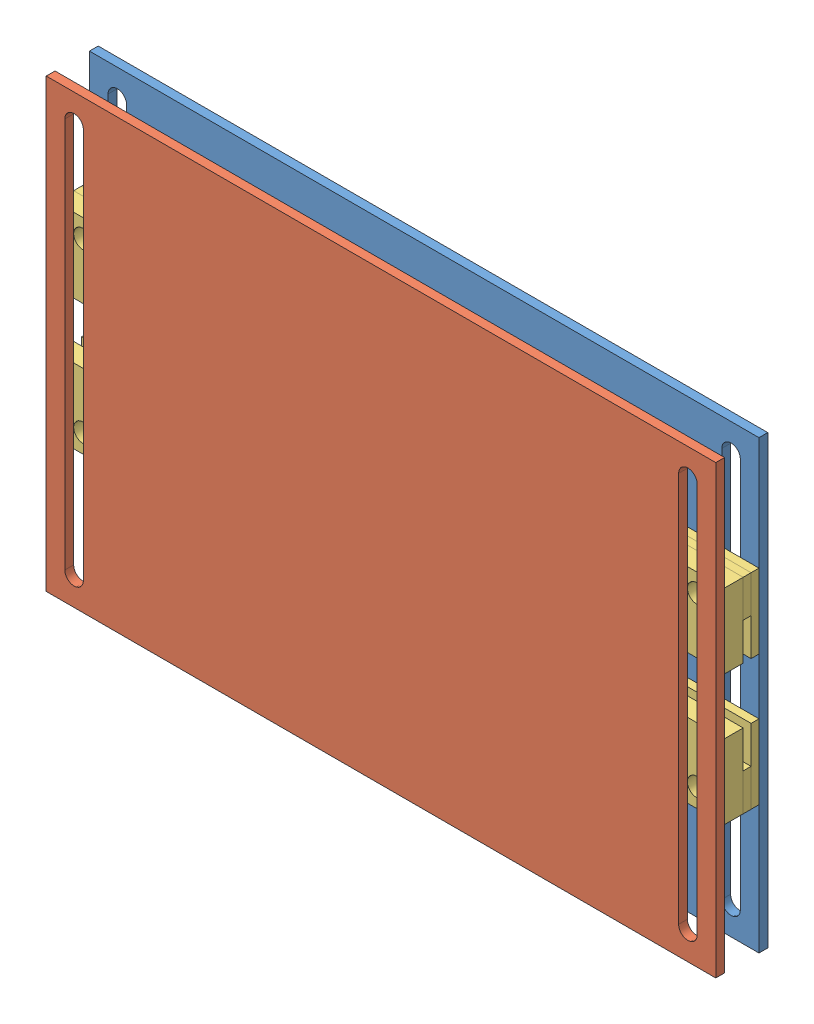
SolidWorks assembly Assem1, configuration Default. Lengths in mm.
Overall size (228.6 152.4 17.75).
4 component instances, 3 part files, 11 mates.
Components (placement in the parent):
- BackPanel-1: BackPanel [Default] at (50.7848 136.7914 180.3131) size (228.6 152.4 3)
- LightPanels-1: LightPanels [Default] at (50.7848 136.7914 195.0631) size (228.6 152.4 3)
- Traps-1: Traps [Default] at (50.7848 168.0579 187.3631) size (228.6 25.4 11.75)
- Traps-3: Traps [Default] at (50.7848 110.8049 187.3631) x (-1 0 0) z (0 0 1) size (228.6 25.4 11.75)
Mates (geometry in assembly coordinates):
- Parallel1: parallel anti-aligned: plane of BackPanel-1 through (50.7848 136.7914 183.3131) normal (0 0 1); plane of LightPanels-1 through (50.7848 136.7914 195.0631) normal (0 0 -1)
- Coincident2: coincident aligned: plane of BackPanel-1 through (165.0848 212.9914 183.3131) normal (0 1 0); plane of LightPanels-1 through (165.0848 212.9914 198.0631) normal (0 1 0)
- Coincident3: coincident aligned: plane of BackPanel-1 through (165.0848 60.5914 183.3131) normal (1 0 0); plane of LightPanels-1 through (165.0848 60.5914 198.0631) normal (1 0 0)
- Coincident4: coincident anti-aligned: plane of LightPanels-1 through (50.7848 136.7914 195.0631) normal (0 0 -1); plane of Traps-1 through (165.0848 168.0579 195.0631) normal (0 0 1)
- Tangent1: tangent anti-aligned: plane of LightPanels-1 through (152.3848 203.4664 198.0631) normal (1 0 0); cylinder of Traps-1 through (155.5598 168.0579 174.3328) axis (0 0 1) radius 3.175
- Parallel2: parallel aligned: plane of LightPanels-1 through (165.0848 212.9914 198.0631) normal (0 1 0); plane of Traps-1 through (165.0848 174.4079 187.3631) normal (0 1 0)
- Tangent2: tangent anti-aligned: plane of BackPanel-1 through (-50.8152 203.4664 183.3131) normal (-1 0 0); cylinder of Traps-1 through (-53.9902 168.0579 174.3328) axis (0 0 1) radius 3.175
- Coincident6: coincident anti-aligned: plane of BackPanel-1 through (50.7848 136.7914 183.3131) normal (0 0 1); plane of Traps-1 through (165.0848 168.0579 183.3131) normal (0 0 -1)
- Coincident11: coincident anti-aligned: plane of BackPanel-1 through (50.7848 136.7914 183.3131) normal (0 0 1); plane of Traps-3 through (-63.5152 110.8049 183.3131) normal (0 0 -1)
- Parallel5: parallel anti-aligned: plane of Traps-1 through (165.0848 149.0079 187.3631) normal (0 -1 0); plane of Traps-3 through (-63.5152 129.8549 187.3631) normal (0 1 0)
- Tangent4: tangent anti-aligned: plane of BackPanel-1 through (158.7348 203.4664 183.3131) normal (-1 0 0); cylinder of Traps-3 through (155.5598 110.8049 174.3328) axis (0 0 1) radius 3.175
